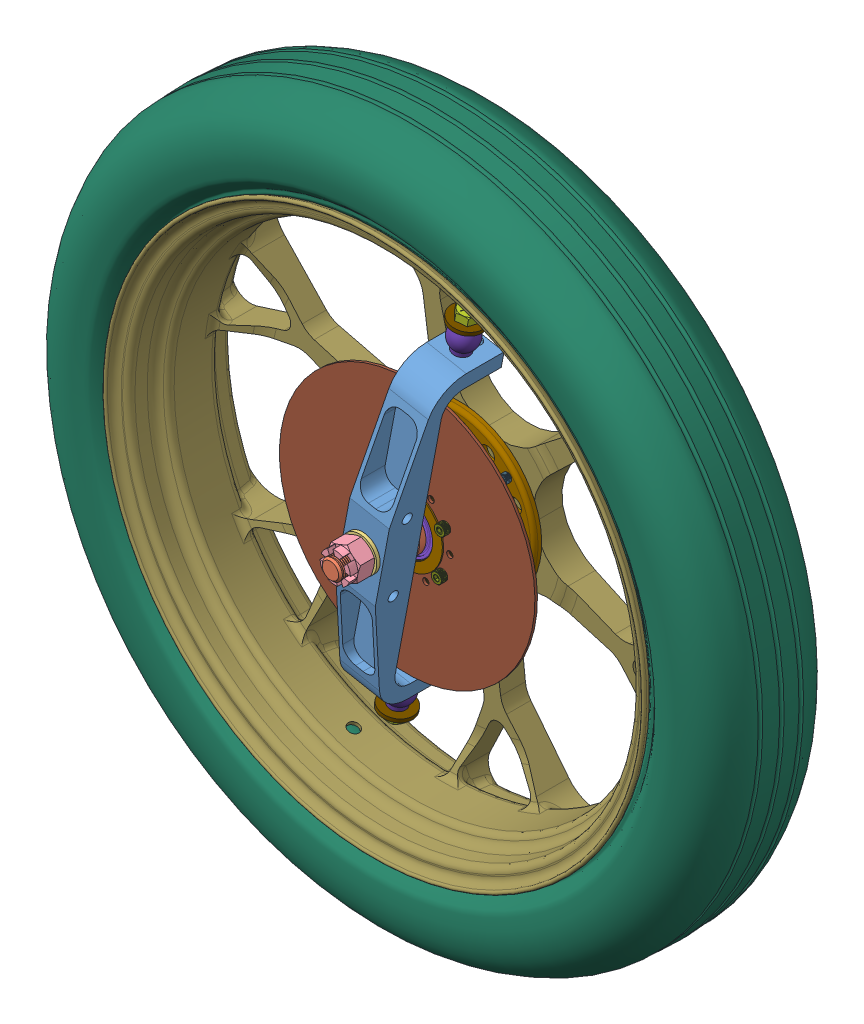
SolidWorks assembly SpindleAssy, configuration Default. Lengths in mm.
Overall size (616.2 616.2 50000).
36 component instances, 18 part files, 73 mates.
Components (placement in the parent):
- Knuckle-1: Knuckle [Default] at (82.0121 130.0239 204.0915) size (78.12 253.33 73.5)
- Spindle_Light-1: Spindle_Light [Default] at (82.0121 130.0239 204.0915) x (0 0 -1) z (0.185408 0.982662 0) size (50000 34 30)
- M16 98688A121_General Purpose Zinc-Plated Steel Washer-1: M16 98688A121_General Purpose Zinc-Plated Steel Washer [98688A121] at (82.0121 130.0239 232.5915) x (0.99983 -0.018445 0) z (0 0 1) size (28 28 2.7)
- M16x1-5 93760A128_Steel Locknut for Use with Cotter Pins-1: M16x1-5 93760A128_Steel Locknut for Use with Cotter Pins [93760A128] at (82.0121 130.0239 254.2915) x (0.982886 -0.184217 0) z (0 0 1) size (24 27.71 19.76)
- M14 98689A119_General Purpose 18-8 Stainless Steel Washer-1: M14 98689A119_General Purpose 18-8 Stainless Steel Washer [98689A119] at (82.0121 130.0239 138.2415) size (24 24 2.7)
- M14x1-5 93760A127_Steel Locknut for Use with Cotter Pins-1: M14x1-5 93760A127_Steel Locknut for Use with Cotter Pins [93760A127] at (82.0121 130.0239 120.8915) x (-0.661913 -0.74958 0) z (0 0 -1) size (22 25.4 16.76)
- 91257A659_Zinc Yellow-Chromate Plated Hex Head Screw-2: 91257A659_Zinc Yellow-Chromate Plated Hex Head Screw [91257A659] at (58.1191 3.3909 177.4439) x (0.185408 0.982662 0) z (0.110595 -0.020867 0.993646) size (57.6 16.5 14.29)
- 91257A659_Zinc Yellow-Chromate Plated Hex Head Screw-3: 91257A659_Zinc Yellow-Chromate Plated Hex Head Screw [91257A659] at (105.9051 256.6568 177.4439) x (-0.185408 -0.982662 0) z (-0.685297 0.129301 0.716693) size (57.6 16.5 14.29)
- SKF_6004-2Z.stp-1: SKF_6004-2Z.stp [Default] at (82.0121 130.0239 185.0915) x (0 0 1) z (-0.58163 0.813454 0) size (12 42 42)
- Hub5-16-1: Hub5-16 [Default] at (82.0121 130.0239 173.6746) x (-0.944813 0.32761 0) z (0.32761 0.944813 0) size (130 85 130)
- SKF_6003-2Z.stp-1: SKF_6003-2Z.stp [Default] at (82.0121 130.0239 149.5915) x (0 0 -1) z (0.973183 -0.230032 0) size (10 35 35)
- BasicBrakeDisc-1: BasicBrakeDisc [Default] at (82.0121 130.0239 195.0915) x (0.071911 0.997411 0) z (0 0 1) size (203 203 3.17)
- rimmachined v13.2-1: rimmachined v13.2 [Default] at (82.0121 130.0239 177.3915) x (0 0 -1) z (-0.981935 -0.189217 0) size (93.59 431.57 431.57)
- 92415A381_Zinc-Plated Steel Unthreaded Spacer-2: 92415A381_Zinc-Plated Steel Unthreaded Spacer [92415A381] at (71.0682 186.982 155.2387) size (7.94 7.94 7.21)
- 92415A381_Zinc-Plated Steel Unthreaded Spacer-3: 92415A381_Zinc-Plated Steel Unthreaded Spacer [92415A381] at (27.2129 149.0252 155.2387) size (7.94 7.94 7.21)
- 92415A381_Zinc-Plated Steel Unthreaded Spacer-4: 92415A381_Zinc-Plated Steel Unthreaded Spacer [92415A381] at (38.1569 92.0671 155.2387) size (7.94 7.94 7.21)
- 92415A381_Zinc-Plated Steel Unthreaded Spacer-5: 92415A381_Zinc-Plated Steel Unthreaded Spacer [92415A381] at (92.956 73.0657 155.2387) size (7.94 7.94 7.21)
- 92415A381_Zinc-Plated Steel Unthreaded Spacer-6: 92415A381_Zinc-Plated Steel Unthreaded Spacer [92415A381] at (136.8113 111.0225 155.2387) size (7.94 7.94 7.21)
- 92415A381_Zinc-Plated Steel Unthreaded Spacer-7: 92415A381_Zinc-Plated Steel Unthreaded Spacer [92415A381] at (125.8674 167.9807 155.2387) size (7.94 7.94 7.21)
- 8-32x3-8 92196A192_18-8 Stainless Steel Socket Head Screw-1: 8-32x3-8 92196A192_18-8 Stainless Steel Socket Head Screw [92196A192] at (92.956 73.0657 158.4118) size (6.85 6.85 14.15)
- 8-32x3-8 92196A192_18-8 Stainless Steel Socket Head Screw-2: 8-32x3-8 92196A192_18-8 Stainless Steel Socket Head Screw [92196A192] at (38.1569 92.0671 158.4118) size (6.85 6.85 14.15)
- 8-32x3-8 92196A192_18-8 Stainless Steel Socket Head Screw-3: 8-32x3-8 92196A192_18-8 Stainless Steel Socket Head Screw [92196A192] at (136.8113 111.0225 158.4118) size (6.85 6.85 14.15)
- 8-32x3-8 92196A192_18-8 Stainless Steel Socket Head Screw-4: 8-32x3-8 92196A192_18-8 Stainless Steel Socket Head Screw [92196A192] at (125.8674 167.9807 158.4118) size (6.85 6.85 14.15)
- 8-32x3-8 92196A192_18-8 Stainless Steel Socket Head Screw-5: 8-32x3-8 92196A192_18-8 Stainless Steel Socket Head Screw [92196A192] at (71.0682 186.982 158.4118) size (6.85 6.85 14.15)
- 8-32x3-8 92196A192_18-8 Stainless Steel Socket Head Screw-6: 8-32x3-8 92196A192_18-8 Stainless Steel Socket Head Screw [92196A192] at (27.2129 149.0252 158.4118) size (6.85 6.85 14.15)
- Michelin Tire-1: Michelin Tire [Default] at (82.0121 130.0239 177.3915) x (0 0 1) z (-0.993534 -0.113534 0) size (101.13 556.61 556.61)
- M5x10 91290A224_Alloy Steel Socket Head Screw-1: M5x10 91290A224_Alloy Steel Socket Head Screw [91290A224] at (84.4571 163.9358 194.5915) x (0.901899 0.431946 0) z (0 0 1) size (8.5 8.5 15.31)
- M5x10 91290A224_Alloy Steel Socket Head Screw-2: M5x10 91290A224_Alloy Steel Socket Head Screw [91290A224] at (53.866 149.0973 194.5915) x (-0.609316 -0.792927 0) z (0 0 1) size (8.5 8.5 15.31)
- M5x10 91290A224_Alloy Steel Socket Head Screw-3: M5x10 91290A224_Alloy Steel Socket Head Screw [91290A224] at (112.6032 144.8625 194.5915) x (0.740699 0.671837 0) z (0 0 1) size (8.5 8.5 15.31)
- M5x10 91290A224_Alloy Steel Socket Head Screw-4: M5x10 91290A224_Alloy Steel Socket Head Screw [91290A224] at (110.1583 110.9505 194.5915) x (-0.161403 -0.986889 0) z (0 0 1) size (8.5 8.5 15.31)
- M5x10 91290A224_Alloy Steel Socket Head Screw-5: M5x10 91290A224_Alloy Steel Socket Head Screw [91290A224] at (51.421 115.1853 194.5915) x (0.079005 -0.996874 0) z (0 0 1) size (8.5 8.5 15.31)
- M5x10 91290A224_Alloy Steel Socket Head Screw-6: M5x10 91290A224_Alloy Steel Socket Head Screw [91290A224] at (79.5671 96.1119 194.5915) x (-0.159143 -0.987256 0) z (0 0 1) size (8.5 8.5 15.31)
- BallSuper-Swivel  Joint Rod End6960T231_-1: BallSuper-Swivel  Joint Rod End6960T231_ [6960T231] at (75.3125 -8.1245 178.3098) x (-0.044663 0.008427 0.998967) z (-0.185408 -0.982662 0) size (20.64 20.64 22.23)
- BallSuper-Swivel  Joint Rod End6960T231_-2: BallSuper-Swivel  Joint Rod End6960T231_ [6960T231] at (109.0836 264.3285 196.4178) x (0.978736 -0.184667 -0.089292) z (0.185408 0.982662 0) size (20.64 20.64 22.23)
- 3-8 98029A046_Black-Oxide Steel Oversized Washer-1: 3-8 98029A046_Black-Oxide Steel Oversized Washer [98029A046] at (54.2751 -16.9823 177.4439) x (0.965511 -0.182172 -0.186017) z (0.185408 0.982662 0) size (25.4 25.4 2.98)
- 3-8 98029A046_Black-Oxide Steel Oversized Washer-2: 3-8 98029A046_Black-Oxide Steel Oversized Washer [98029A046] at (109.7491 277.0301 177.4439) x (0.965511 -0.182172 -0.186017) z (0.185408 0.982662 0) size (25.4 25.4 2.98)
Mates (geometry in assembly coordinates):
- Coincident1: coincident anti-aligned: circle of Knuckle-1; circle of Spindle_Light-1
- Concentric1: concentric aligned: circle of Knuckle-1; circle of M16 98688A121_General Purpose Zinc-Plated Steel Washer-1
- Concentric2: concentric aligned: circle of M16 98688A121_General Purpose Zinc-Plated Steel Washer-1; circle of M16x1-5 93760A128_Steel Locknut for Use with Cotter Pins-1
- Coincident2: coincident anti-aligned: plane of Knuckle-1 through (82.0121 130.0239 232.5915) normal (0 0 1); plane of M16 98688A121_General Purpose Zinc-Plated Steel Washer-1 through (82.0121 130.0239 232.5915) normal (0 0 -1)
- Coincident3: coincident anti-aligned: plane of M16 98688A121_General Purpose Zinc-Plated Steel Washer-1 through (82.0121 130.0239 235.2915) normal (0 0 1); plane of M16x1-5 93760A128_Steel Locknut for Use with Cotter Pins-1 through (84.5647 143.6431 235.2915) normal (0 0 -1)
- Parallel1: parallel aligned: plane of Spindle_Light-1 through (82.0121 130.0239 258.0915) normal (0 0 1); plane of M16x1-5 93760A128_Steel Locknut for Use with Cotter Pins-1 through (82.0121 130.0239 248.2915) normal (0 0 1)
- Concentric3: concentric anti-aligned: circle of M14 98689A119_General Purpose 18-8 Stainless Steel Washer-1; circle of M14x1-5 93760A127_Steel Locknut for Use with Cotter Pins-1
- Coincident5: coincident anti-aligned: plane of M14 98689A119_General Purpose 18-8 Stainless Steel Washer-1 through (82.0121 130.0239 136.8915) normal (0 0 -1); plane of M14x1-5 93760A127_Steel Locknut for Use with Cotter Pins-1 through (75.0117 150.8804 136.8915) normal (0 0 1)
- Concentric4: concentric anti-aligned: circle of Spindle_Light-1; circle of M14 98689A119_General Purpose 18-8 Stainless Steel Washer-1
- Perpendicular1: perpendicular: line of Knuckle-1 through (84.6232 230.1587 204.0915) axis (-0.185408 -0.982662 0); line of Spindle_Light-1 through (76.9319 146.2471 204.0915) axis (0.982662 -0.185408 0)
- Concentric5: concentric aligned: circle of Knuckle-1; circle of Super-Swivel Ball Joint Ball End2-1
- Coincident7: coincident anti-aligned: plane of Knuckle-1 through (89.6292 256.6906 232.5915) normal (0.185408 0.982662 0); plane of Super-Swivel Ball Joint Ball End2-1 through (107.5018 254.0508 172.0915) normal (-0.20131 -0.979528 0)
- Concentric6: concentric anti-aligned: circle of Knuckle-1; circle of Super-Swivel Ball Joint Ball End2-2
- Coincident8: coincident anti-aligned: plane of Knuckle-1 through (74.395 3.3572 232.5915) normal (-0.185408 -0.982662 0); plane of Super-Swivel Ball Joint Ball End2-2 through (56.5224 5.997 172.0915) normal (0.20131 0.979528 0)
- Coincident11: coincident anti-aligned: circle of Knuckle-1; circle of SteerArm-1
- Coincident12: coincident anti-aligned: circle of Knuckle-1; circle of SteerArm-1
- Concentric7: concentric anti-aligned: circle of Spindle_Light-1; circle of SKF_6004-2Z.stp-1
- Coincident13: coincident anti-aligned: plane of Spindle_Light-1 through (70.2202 132.2488 197.0915) normal (0 0 -1); plane of SKF_6004-2Z.stp-1 through (90.6347 136.1891 197.0915) normal (0 0 1)
- Coincident14: coincident anti-aligned: plane of SKF_6004-2Z.stp-1 through (98.6066 141.8891 185.0915) normal (0 0 -1); plane of Hub5-16-1 through (64.0607 136.2485 185.0915) normal (0 0 1)
- Concentric8: concentric aligned: cylinder of SKF_6004-2Z.stp-1 through (82.0121 130.0239 235.0915) axis (0 0 1) radius 21; cylinder of Hub5-16-1 through (82.0121 130.0239 1099.7023) axis (0 0 1) radius 21
- Concentric9: concentric anti-aligned: cylinder of Hub5-16-1 through (82.0121 130.0239 1099.7023) axis (0 0 1) radius 17.5; cylinder of SKF_6003-2Z.stp-1 through (82.0121 130.0239 99.5915) axis (0 0 -1) radius 17.5
- Coincident15: coincident anti-aligned: plane of Hub5-16-1 through (67.3675 135.1018 149.5915) normal (0 0 -1); plane of SKF_6003-2Z.stp-1 through (85.9687 146.7626 149.5915) normal (0 0 1)
- Coincident16: coincident anti-aligned: plane of M14 98689A119_General Purpose 18-8 Stainless Steel Washer-1 through (82.0121 130.0239 139.5915) normal (0 0 1); plane of SKF_6003-2Z.stp-1 through (84.0364 138.5879 139.5915) normal (0 0 -1)
- Concentric10: concentric aligned: circle of Hub5-16-1; circle of BasicBrakeDisc-1
- Coincident18: coincident anti-aligned: plane of Hub5-16-1 through (54.6125 139.5246 195.0915) normal (0 0 1); plane of BasicBrakeDisc-1 through (82.0121 130.0239 195.0915) normal (0 0 -1)
- Concentric11: concentric anti-aligned: cylinder of Hub5-16-1 through (82.0121 130.0239 1099.7023) axis (0 0 1) radius 47; cylinder of rimmachined v13.2-1 through (82.0121 130.0239 168.2915) axis (0 0 -1) radius 47.005
- Coincident19: coincident aligned: circle of Hub5-16-1; circle of 92415A381_Zinc-Plated Steel Unthreaded Spacer-5
- Coincident20: coincident aligned: circle of Hub5-16-1; circle of 92415A381_Zinc-Plated Steel Unthreaded Spacer-4
- Coincident21: coincident aligned: circle of Hub5-16-1; circle of 92415A381_Zinc-Plated Steel Unthreaded Spacer-3
- Coincident22: coincident aligned: circle of Hub5-16-1; circle of 92415A381_Zinc-Plated Steel Unthreaded Spacer-2
- Coincident23: coincident aligned: circle of Hub5-16-1; circle of 92415A381_Zinc-Plated Steel Unthreaded Spacer-7
- Coincident24: coincident aligned: circle of Hub5-16-1; circle of 92415A381_Zinc-Plated Steel Unthreaded Spacer-6
- Concentric121: concentric anti-aligned: cylinder of Hub5-16-1 through (92.956 73.0657 151.0915) axis (0 0 1) radius 2.15; cylinder of 8-32x3-8 92196A192_18-8 Stainless Steel Socket Head Screw-1 through (92.956 73.0657 151.5665) axis (0 0 -1) radius 2.0828
- Coincident251: coincident anti-aligned: plane of Hub5-16-1 through (23.4337 150.3357 161.0915) normal (0 0 1); plane of 8-32x3-8 92196A192_18-8 Stainless Steel Socket Head Screw-1 through (89.6985 73.0657 161.0915) normal (0 0 -1)
- Concentric131: concentric anti-aligned: cylinder of Hub5-16-1 through (38.1569 92.0671 151.0915) axis (0 0 1) radius 2.15; cylinder of 8-32x3-8 92196A192_18-8 Stainless Steel Socket Head Screw-2 through (38.1569 92.0671 151.5665) axis (0 0 -1) radius 2.0828
- Coincident261: coincident anti-aligned: plane of Hub5-16-1 through (23.4337 150.3357 161.0915) normal (0 0 1); plane of 8-32x3-8 92196A192_18-8 Stainless Steel Socket Head Screw-2 through (34.8993 92.0671 161.0915) normal (0 0 -1)
- Concentric141: concentric anti-aligned: cylinder of Hub5-16-1 through (136.8113 111.0225 151.0915) axis (0 0 1) radius 2.15; cylinder of 8-32x3-8 92196A192_18-8 Stainless Steel Socket Head Screw-3 through (136.8113 111.0225 151.5665) axis (0 0 -1) radius 2.0828
- Coincident271: coincident anti-aligned: plane of Hub5-16-1 through (23.4337 150.3357 161.0915) normal (0 0 1); plane of 8-32x3-8 92196A192_18-8 Stainless Steel Socket Head Screw-3 through (133.5537 111.0225 161.0915) normal (0 0 -1)
- Concentric151: concentric anti-aligned: cylinder of Hub5-16-1 through (125.8674 167.9807 151.0915) axis (0 0 1) radius 2.15; cylinder of 8-32x3-8 92196A192_18-8 Stainless Steel Socket Head Screw-4 through (125.8674 167.9807 151.5665) axis (0 0 -1) radius 2.0828
- Coincident281: coincident anti-aligned: plane of Hub5-16-1 through (23.4337 150.3357 161.0915) normal (0 0 1); plane of 8-32x3-8 92196A192_18-8 Stainless Steel Socket Head Screw-4 through (122.6098 167.9807 161.0915) normal (0 0 -1)
- Concentric161: concentric anti-aligned: cylinder of Hub5-16-1 through (71.0682 186.982 151.0915) axis (0 0 1) radius 2.15; cylinder of 8-32x3-8 92196A192_18-8 Stainless Steel Socket Head Screw-5 through (71.0682 186.982 151.5665) axis (0 0 -1) radius 2.0828
- Coincident291: coincident anti-aligned: plane of Hub5-16-1 through (23.4337 150.3357 161.0915) normal (0 0 1); plane of 8-32x3-8 92196A192_18-8 Stainless Steel Socket Head Screw-5 through (67.8106 186.982 161.0915) normal (0 0 -1)
- Concentric171: concentric anti-aligned: cylinder of Hub5-16-1 through (27.2129 149.0252 151.0915) axis (0 0 1) radius 2.15; cylinder of 8-32x3-8 92196A192_18-8 Stainless Steel Socket Head Screw-6 through (27.2129 149.0252 151.5665) axis (0 0 -1) radius 2.0828
- Coincident301: coincident anti-aligned: plane of Hub5-16-1 through (23.4337 150.3357 161.0915) normal (0 0 1); plane of 8-32x3-8 92196A192_18-8 Stainless Steel Socket Head Screw-6 through (23.9554 149.0252 161.0915) normal (0 0 -1)
- Tangent1: tangent anti-aligned: plane of rimmachined v13.2-1 through (88.5859 74.7696 150.7915) normal (0.981935 0.189217 0); cylinder of 92415A381_Zinc-Plated Steel Unthreaded Spacer-5 through (92.956 73.0657 151.6669) axis (0 0 1) radius 3.9688
- Coincident31: coincident anti-aligned: plane of Hub5-16-1 through (37.6059 145.4215 155.0915) normal (0 0 -1); plane of rimmachined v13.2-1 through (89.5808 90.7465 155.0915) normal (0 0 1)
- Concentric18: concentric aligned: cone of rimmachined v13.2-1 through (82.0121 130.0239 200.42) axis (0 0 -1); cylinder of Michelin Tire-1 through (82.0121 130.0239 74.6686) axis (0 0 -1) radius 203
- Coincident32: coincident anti-aligned: plane of rimmachined v13.2-1 through (82.0121 130.0239 177.3915) normal (0 0 -1); plane of Michelin Tire-1 through (82.0121 130.0239 177.3915) normal (0 0 1)
- Concentric19: concentric anti-aligned: cylinder of Hub5-16-1 through (67.1735 160.615 185.0915) axis (0 0 1) radius 2; cylinder of BasicBrakeDisc-1 through (67.1735 160.615 197.0915) axis (0 0 -1) radius 2.497
- Concentric20: concentric anti-aligned: circle of BasicBrakeDisc-1; circle of M5x10 91290A224_Alloy Steel Socket Head Screw-2
- Coincident33: coincident anti-aligned: plane of BasicBrakeDisc-1 through (82.0121 130.0239 197.0915) normal (0 0 1); plane of M5x10 91290A224_Alloy Steel Socket Head Screw-2 through (56.3032 152.269 197.0915) normal (0 0 -1)
- Concentric21: concentric anti-aligned: circle of BasicBrakeDisc-1; circle of M5x10 91290A224_Alloy Steel Socket Head Screw-1
- Concentric22: concentric anti-aligned: circle of BasicBrakeDisc-1; circle of M5x10 91290A224_Alloy Steel Socket Head Screw-3
- Concentric23: concentric anti-aligned: circle of BasicBrakeDisc-1; circle of M5x10 91290A224_Alloy Steel Socket Head Screw-4
- Concentric24: concentric anti-aligned: circle of BasicBrakeDisc-1; circle of M5x10 91290A224_Alloy Steel Socket Head Screw-6
- Concentric25: concentric anti-aligned: circle of BasicBrakeDisc-1; circle of M5x10 91290A224_Alloy Steel Socket Head Screw-5
- Coincident34: coincident anti-aligned: plane of BasicBrakeDisc-1 through (82.0121 130.0239 197.0915) normal (0 0 1); plane of M5x10 91290A224_Alloy Steel Socket Head Screw-1 through (80.8495 162.2081 197.0915) normal (0 0 -1)
- Coincident36: coincident anti-aligned: plane of BasicBrakeDisc-1 through (82.0121 130.0239 197.0915) normal (0 0 1); plane of M5x10 91290A224_Alloy Steel Socket Head Screw-3 through (109.6404 142.1751 197.0915) normal (0 0 -1)
- Coincident37: coincident anti-aligned: plane of BasicBrakeDisc-1 through (82.0121 130.0239 197.0915) normal (0 0 1); plane of M5x10 91290A224_Alloy Steel Socket Head Screw-5 through (51.105 119.1728 197.0915) normal (0 0 -1)
- Coincident38: coincident anti-aligned: plane of BasicBrakeDisc-1 through (82.0121 130.0239 197.0915) normal (0 0 1); plane of M5x10 91290A224_Alloy Steel Socket Head Screw-6 through (80.2037 100.0609 197.0915) normal (0 0 -1)
- Coincident39: coincident anti-aligned: plane of BasicBrakeDisc-1 through (82.0121 130.0239 197.0915) normal (0 0 1); plane of M5x10 91290A224_Alloy Steel Socket Head Screw-4 through (110.8039 114.898 197.0915) normal (0 0 -1)
- Coincident302: coincident anti-aligned: plane of Knuckle-1 through (89.6292 256.6906 232.5915) normal (0.185408 0.982662 0); plane of BallSuper-Swivel  Joint Rod End6960T231_-2 through (105.3518 253.724 177.4439) normal (-0.185408 -0.982662 0)
- Coincident303: coincident anti-aligned: plane of Knuckle-1 through (74.395 3.3572 232.5915) normal (-0.185408 -0.982662 0); plane of BallSuper-Swivel  Joint Rod End6960T231_-1 through (58.6725 6.3237 177.4439) normal (0.185408 0.982662 0)
- Concentric174: concentric aligned: cylinder of Knuckle-1 through (57.5915 0.5946 177.4439) axis (0.185408 0.982662 0) radius 4.7625; cylinder of BallSuper-Swivel  Joint Rod End6960T231_-2 through (105.4989 254.504 177.4439) axis (0.185408 0.982662 0) radius 4.7625
- Concentric175: concentric anti-aligned: cylinder of Knuckle-1 through (57.5915 0.5946 177.4439) axis (0.185408 0.982662 0) radius 4.7625; cylinder of BallSuper-Swivel  Joint Rod End6960T231_-1 through (58.5253 5.5437 177.4439) axis (-0.185408 -0.982662 0) radius 4.7625
- Concentric176: concentric anti-aligned: cylinder of 91257A659_Zinc Yellow-Chromate Plated Hex Head Screw-2 through (53.9984 -18.4487 177.4439) axis (0.185408 0.982662 0) radius 4.7625; cylinder of BallSuper-Swivel  Joint Rod End6960T231_-1 through (58.5253 5.5437 177.4439) axis (-0.185408 -0.982662 0) radius 4.7625
- Concentric177: concentric anti-aligned: cylinder of 91257A659_Zinc Yellow-Chromate Plated Hex Head Screw-2 through (53.9984 -18.4487 177.4439) axis (0.185408 0.982662 0) radius 4.7625; cylinder of 3-8 98029A046_Black-Oxide Steel Oversized Washer-1 through (54.5518 -15.516 177.4439) axis (-0.185408 -0.982662 0) radius 5.1562
- Coincident304: coincident anti-aligned: plane of BallSuper-Swivel  Joint Rod End6960T231_-1 through (54.5518 -15.516 177.4439) normal (-0.185408 -0.982662 0); plane of 3-8 98029A046_Black-Oxide Steel Oversized Washer-1 through (54.5518 -15.516 177.4439) normal (0.185408 0.982662 0)
- Coincident305: coincident anti-aligned: plane of 91257A659_Zinc Yellow-Chromate Plated Hex Head Screw-2 through (50.7613 -17.8379 185.0065) normal (0.185408 0.982662 0); plane of 3-8 98029A046_Black-Oxide Steel Oversized Washer-1 through (53.9984 -18.4487 177.4439) normal (-0.185408 -0.982662 0)
- Concentric178: concentric aligned: circle of BallSuper-Swivel  Joint Rod End6960T231_-2; circle of 3-8 98029A046_Black-Oxide Steel Oversized Washer-2
- Coincident306: coincident anti-aligned: plane of BallSuper-Swivel  Joint Rod End6960T231_-2 through (109.4725 275.5637 177.4439) normal (0.185408 0.982662 0); plane of 3-8 98029A046_Black-Oxide Steel Oversized Washer-2 through (109.4725 275.5637 177.4439) normal (-0.185408 -0.982662 0)
- Concentric179: concentric anti-aligned: cylinder of 91257A659_Zinc Yellow-Chromate Plated Hex Head Screw-3 through (110.0258 278.4965 177.4439) axis (-0.185408 -0.982662 0) radius 4.7625; cylinder of BallSuper-Swivel  Joint Rod End6960T231_-2 through (105.4989 254.504 177.4439) axis (0.185408 0.982662 0) radius 4.7625
- Coincident307: coincident anti-aligned: plane of 91257A659_Zinc Yellow-Chromate Plated Hex Head Screw-3 through (108.0349 278.8721 185.4402) normal (-0.185408 -0.982662 0); plane of 3-8 98029A046_Black-Oxide Steel Oversized Washer-2 through (110.0258 278.4965 177.4439) normal (0.185408 0.982662 0)
